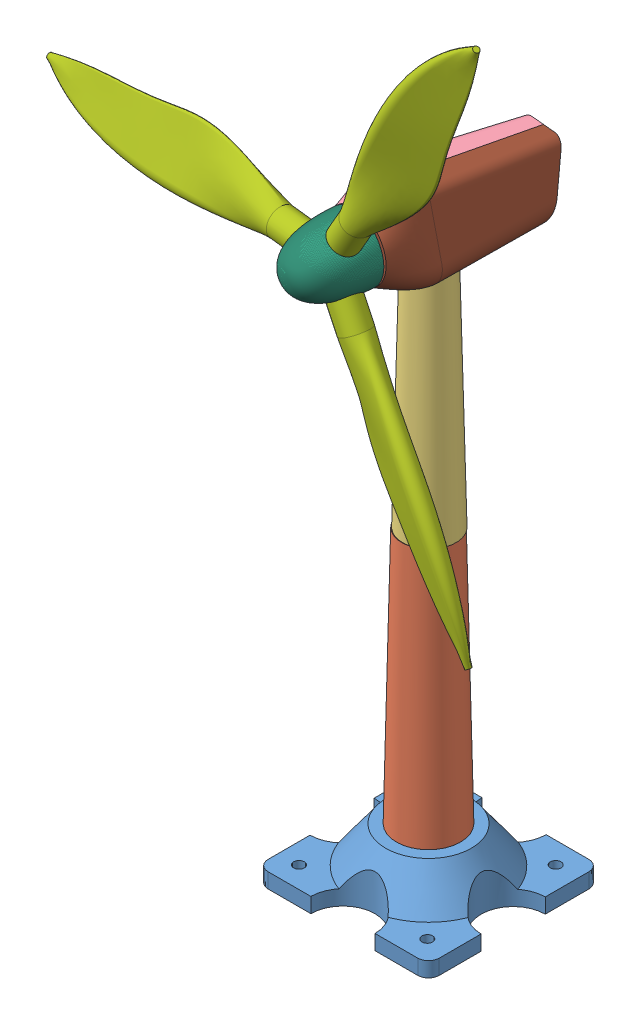
SolidWorks assembly Wind turbine assembly, configuration Default. Lengths in mm.
Overall size (303.61 515.67 146.28).
16 component instances, 11 part files, 25 mates.
Components (placement in the parent):
- base-1: base [Default] at (43.0092 36.32 76.2958) size (101.6 30.48 101.6)
- Wind turbine lower mast-1: Wind turbine lower mast [Default] at (43.0092 54.1 76.2958) x (0 1 0) z (0.144541 0 -0.989499) size (165.1 38.1 38.1)
- Wind turbine upper mast-1: Wind turbine upper mast [Default] at (43.2972 206.5 76.0811) x (0 1 0) z (-0.144541 0 0.989499) size (152.4 31.75 31.75)
- nacelle-1: nacelle [Default] at (41.9965 381.76 89.9904) x (0.995656 0 0.093109) z (-0.093109 0 0.995656) size (28.09 50.05 102.69)
- connecting rod-1: connecting rod [Default] at (43.2972 352.55 76.0811) size (9.53 38.1 9.53)
- Turbine Hub-1: Turbine Hub [Default] at (35.9658 381.76 154.4791) x (-0.870279 -0.485789 -0.081384) z (-0.093109 0 0.995656) size (38.44 38.57 38.1)
- Wind turbine blade-1: Wind turbine blade [Default] at (42.231 388.2961 129.5542) x (-0.204598 0.175825 -0.962925) z (0.834359 -0.483075 -0.265488) size (16.85 177.81 44.93)
- Wind turbine blade-3: Wind turbine blade [Default] at (42.0164 375.0996 129.5341) x (0.385146 0.16615 -0.907776) z (-0.78595 -0.456492 -0.41701) size (16.85 177.81 44.93)
- Wind turbine blade-4: Wind turbine blade [Default] at (30.7449 381.8845 128.48) x (0.081932 -0.341975 -0.936131) z (0.047126 0.939567 -0.339105) size (16.85 177.81 44.93)
- Turbine Hub-2: Turbine Hub [Default] at (35.9658 381.76 154.4791) x (0.016262 0.999867 0.001521) z (-0.093109 0 0.995656) size (38.44 38.57 38.1)
- Turbine Hub-3: Turbine Hub [Default] at (35.9658 381.76 154.4791) x (0.854018 -0.514078 0.079863) z (-0.093109 0 0.995656) size (38.44 38.57 38.1)
- 2780T350_HIGH-LOAD BEARING-1: 2780T350_HIGH-LOAD BEARING [2780T35] at (42.0113 381.76 89.8324) x (0.408831 0.911809 0.038232) z (-0.093109 0 0.995656) size (23.02 23.02 7.94)
- 2780T350_HIGH-LOAD BEARING-2: 2780T350_HIGH-LOAD BEARING [2780T35] at (46.1499 381.76 45.5755) x (0.970525 0.223258 0.090758) z (-0.093109 0 0.995656) size (23.02 23.02 7.94)
- Turbine main shaft-1: Turbine main shaft [Default] at (42.7651 381.76 81.7713) x (-0.634083 -0.770988 -0.059296) z (0.767639 -0.63685 0.071786) size (9.53 95.25 9.53)
- 98408A134_SIDE-MOUNT EXTERNAL RETAINING RING  E-STYLE-1: 98408A134_SIDE-MOUNT EXTERNAL RETAINING RING  E-STYLE [98408A134] at (46.8588 381.76 37.9954) x (0.093109 0 -0.995656) z (0.995656 0 0.093109) size (0.89 16.76 15.36)
- Mirrornacelle-3: Mirrornacelle [Default] at (41.9965 381.76 89.9904) x (-0.995656 0 -0.093109) z (0.093109 0 -0.995656) size (28.12 50.05 102.69)
Mates (geometry in assembly coordinates):
- Parallel1: parallel anti-aligned: plane of base-1 through (43.0092 54.1 76.2958) normal (0 1 0); plane of Wind turbine lower mast-1 through (43.0092 54.1 76.2958) normal (0 -1 0)
- Coincident2: coincident anti-aligned: plane of base-1 through (43.0092 54.1 76.2958) normal (0 1 0); plane of Wind turbine lower mast-1 through (43.0092 54.1 76.2958) normal (0 -1 0)
- Concentric4: concentric anti-aligned: cylinder of base-1 through (43.0092 54.1 76.2958) axis (0 1 0) radius 19.05; cylinder of Wind turbine lower mast-1 through (43.0092 48.3621 76.2958) axis (0 -1 0) radius 19.05
- Coincident3: coincident anti-aligned: plane of Wind turbine lower mast-1 through (43.0092 206.5 76.2958) normal (0 1 0); plane of Wind turbine upper mast-1 through (43.3484 206.5 76.1776) normal (0 -1 0)
- Coincident4: coincident anti-aligned: plane of Wind turbine lower mast-1 through (43.0092 206.5 76.2958) normal (0 1 0); plane of Wind turbine upper mast-1 through (43.3484 206.5 76.1776) normal (0 -1 0)
- Coincident5: coincident anti-aligned: plane of Wind turbine lower mast-1 through (39.407 206.5 65.9489) normal (-0.435309 0 0.900281); plane of Wind turbine upper mast-1 through (53.356 206.5 72.6936) normal (0.435309 0 -0.900281)
- Coincident6: coincident anti-aligned: plane of Wind turbine lower mast-1 through (46.6113 206.5 86.6426) normal (-0.900281 0 -0.435309); plane of Wind turbine upper mast-1 through (46.8324 206.5 86.1852) normal (0.900281 0 0.435309)
- Lock2: lock: unknown of Wind turbine lower mast-1; unknown of Wind turbine upper mast-1
- Tangent3: tangent: circle of Wind turbine upper mast-1; curve of nacelle-1
- Lock4: lock: unknown of Wind turbine upper mast-1; unknown of nacelle-1
- Concentric6: concentric anti-aligned: cylinder of Wind turbine upper mast-1 through (43.3484 333.5 76.1776) axis (0 1 0) radius 4.826; cylinder of connecting rod-1 through (43.3484 371.6 76.1776) axis (0 -1 0) radius 4.7625
- Coincident9: coincident anti-aligned: plane of Wind turbine upper mast-1 through (43.3484 333.5 76.1776) normal (0 1 0); plane of connecting rod-1 through (43.3484 333.5 76.1776) normal (0 -1 0)
- Concentric7: concentric anti-aligned: cylinder of nacelle-1 through (26.8685 381.76 115.3115) axis (-0.388106 0 0.921615) radius 6.35; cylinder of Turbine Hub-1 through (22.6468 381.76 125.3366) axis (0.388106 0 -0.921615) radius 4.826
- Distance2: distance = 1.27 mm anti-aligned: plane of nacelle-1; plane of Turbine Hub-1
- Concentric9: concentric aligned: cylinder of Turbine Hub-1 through (31.1874 357.4418 128.9332) axis (-0.32818 0.934451 -0.138202) radius 8.255; cylinder of Wind turbine blade-1 through (33.4833 350.9045 129.9) axis (-0.32818 0.934451 -0.138202) radius 8.255
- Coincident17: coincident anti-aligned: plane of Turbine Hub-1; plane of Wind turbine blade-1
- Angle4: planar angle = 0.349066 rad aligned: plane of Wind turbine blade-1; plane of Turbine Hub-1
- Concentric11: concentric aligned: cylinder of nacelle-1 through (26.8685 381.76 115.3115) axis (-0.388106 0 0.921615) radius 11.43; cylinder of 2780T350_HIGH-LOAD BEARING-1 through (36.4479 381.76 92.564) axis (-0.388106 0 0.921615) radius 11.5094
- Coincident23: coincident anti-aligned: plane of nacelle-1 through (36.4479 393.19 92.564) normal (0.388106 0 -0.921615); plane of 2780T350_HIGH-LOAD BEARING-1 through (27.1096 386.323 88.6315) normal (-0.388106 0 0.921615)
- Concentric12: concentric aligned: cylinder of nacelle-1 through (26.8685 381.76 115.3115) axis (-0.388106 0 0.921615) radius 11.43; cylinder of 2780T350_HIGH-LOAD BEARING-2 through (53.6992 381.76 51.5982) axis (-0.388106 0 0.921615) radius 11.5094
- Coincident24: coincident anti-aligned: plane of nacelle-1 through (53.6992 393.19 51.5982) normal (0.388106 0 -0.921615); plane of 2780T350_HIGH-LOAD BEARING-2 through (51.4127 392.5921 50.6353) normal (-0.388106 0 0.921615)
- Concentric13: concentric anti-aligned: cylinder of Turbine Hub-1 through (22.6468 381.76 125.3366) axis (0.388106 0 -0.921615) radius 4.826; cylinder of Turbine main shaft-1 through (59.6139 381.76 37.5528) axis (-0.388106 0 0.921615) radius 4.7625
- Coincident25: coincident anti-aligned: plane of Turbine Hub-1; plane of Turbine main shaft-1
- Concentric15: concentric aligned: cylinder of Turbine main shaft-1 through (22.5709 381.76 125.517) axis (-0.388106 0 0.921615) radius 3.8481; cylinder of 98408A134_SIDE-MOUNT EXTERNAL RETAINING RING  E-STYLE-1 through (58.3667 381.76 40.5145) axis (-0.388106 0 0.921615) radius 6.2926
- Coincident27: coincident anti-aligned: plane of Turbine main shaft-1 through (58.0216 381.76 41.3338) normal (0.388106 0 -0.921615); plane of 98408A134_SIDE-MOUNT EXTERNAL RETAINING RING  E-STYLE-1 through (58.0216 381.76 41.3338) normal (-0.388106 0 0.921615)
